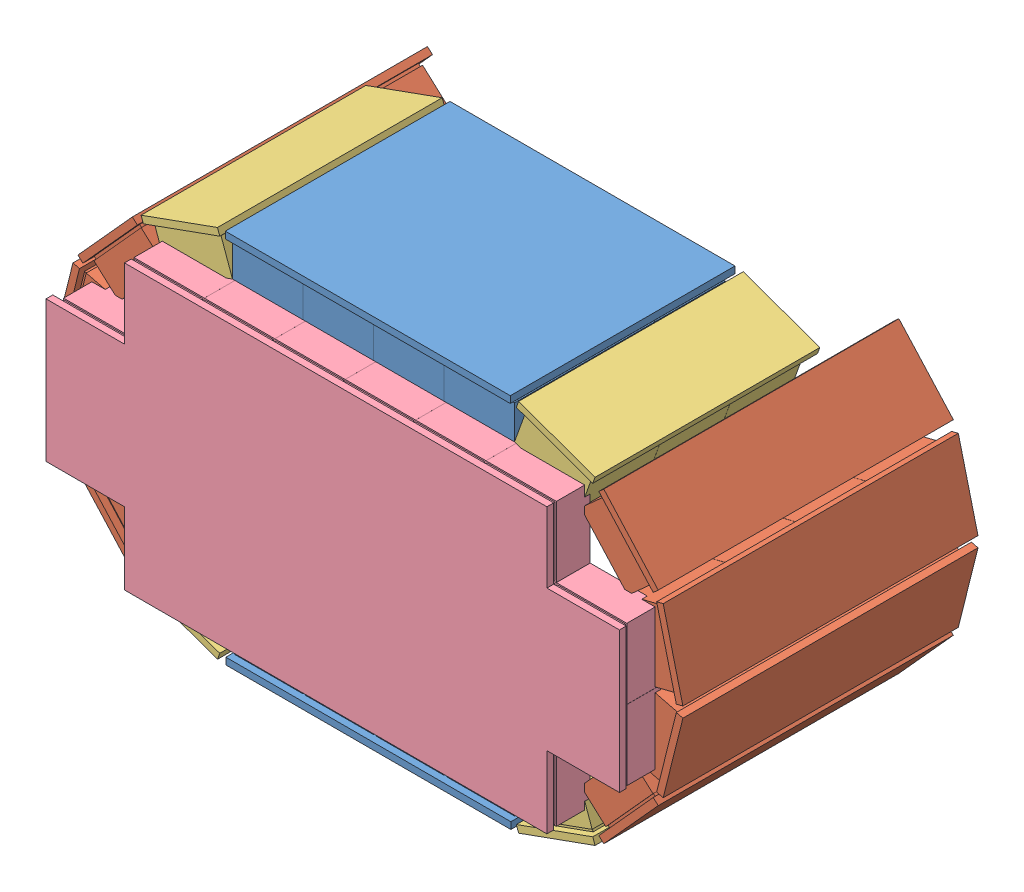
SolidWorks assembly detectorassem, configuration Default. Lengths in mm.
Overall size (517.67 317.54 241.94).
17 component instances, 4 part files, 12 mates.
Components (placement in the parent):
- 52mmTOPBOTTOM-1: 52mmTOPBOTTOM [Default] at (-69.8528 -35.4842 8.7442) size (210.55 32 166)
- SideDetector-1: SideDetector [Default] at (215.9367 233.9438 -54.2197) x (-0.242515 0.970148 0) z (0 0 1) size (268 155.36 218)
  - 52mmX4-1: 52mmX4 [Default] at (-99.1405 6.5957 36.9639) size (60 32 218)
  - 52mmX4-2: 52mmX4 [Default] at (-35.1412 22.594 36.9639) x (0.882373 0.47055 0) z (0 0 1) size (60 32 218)
  - 52mmX4-3: 52mmX4 [Default] at (-163.1399 22.594 36.9639) x (0.882373 -0.47055 0) z (0 0 1) size (60 32 218)
  - 52mmX4-4: 52mmX4 [Default] at (-212.0831 66.8254 36.9639) x (0.557166 -0.830401 0) z (0 0 1) size (60 32 218)
  - 52mmX3-1: 52mmX3 [Default] at (-234.4563 128.8843 62.9639) x (0.100883 -0.994898 0) z (0 0 1) size (60 32 166)
  - 52mmX3-2: 52mmX3 [Default] at (13.802 66.8254 62.9639) x (0.557166 0.830401 0) z (0 0 1) size (60 32 166)
- SideDetector-2: SideDetector [Default] at (-199.3424 -27.5859 -54.2197) x (0.242515 -0.970148 0) z (0 0 1) size (268 155.36 218)
  - 52mmX4-1: 52mmX4 [Default] at (-99.1405 6.5957 36.9639) size (60 32 218)
  - 52mmX4-2: 52mmX4 [Default] at (-35.1412 22.594 36.9639) x (0.882373 0.47055 0) z (0 0 1) size (60 32 218)
  - 52mmX4-3: 52mmX4 [Default] at (-163.1399 22.594 36.9639) x (0.882373 -0.47055 0) z (0 0 1) size (60 32 218)
  - 52mmX4-4: 52mmX4 [Default] at (-212.0831 66.8254 36.9639) x (0.557166 -0.830401 0) z (0 0 1) size (60 32 218)
  - 52mmX3-1: 52mmX3 [Default] at (-234.4563 128.8843 62.9639) x (0.100883 -0.994898 0) z (0 0 1) size (60 32 166)
  - 52mmX3-2: 52mmX3 [Default] at (13.802 66.8254 62.9639) x (0.557166 0.830401 0) z (0 0 1) size (60 32 166)
- 52mmTOPBOTTOM-2: 52mmTOPBOTTOM [Default] at (86.4472 241.8421 8.7442) x (-1 0 0) z (0 0 1) size (210.55 32 166)
- 52mmAnterior-2: 52mmAnterior [Default] at (34.3203 129.1897 115.6812) x (1 0 0) z (0 1 0) size (423.62 32 209.26)
Mates (geometry in assembly coordinates):
- Coincident1: coincident anti-aligned: line of 52mmTOPBOTTOM-1 through (112.4472 -3.4842 87.7442) axis (0 0 -1); line of SideDetector-1/52mmX3-1 through (112.4472 -3.4842 35.8442) axis (0 0 1)
- Coincident2: coincident: point of 52mmTOPBOTTOM-1; point of SideDetector-1/52mmX3-1
- Parallel1: parallel anti-aligned: line of 52mmTOPBOTTOM-1 through (-43.7528 -3.4842 87.7442) axis (1 0 0); line of 52mmTOPBOTTOM-2 through (8.2472 209.8421 87.7442) axis (-1 0 0)
- Parallel2: parallel anti-aligned: line of 52mmTOPBOTTOM-1 through (-95.8528 -3.4842 35.8442) axis (0 0 1); line of 52mmTOPBOTTOM-2 through (-95.8528 209.8421 87.7442) axis (0 0 -1)
- Coincident5: coincident anti-aligned: line of 52mmTOPBOTTOM-1 through (-95.8528 -3.4842 35.8442) axis (0 0 1); line of SideDetector-2/52mmX3-2 through (-95.8528 -3.4842 87.7442) axis (0 0 -1)
- Coincident6: coincident: point of 52mmTOPBOTTOM-1; point of SideDetector-2/52mmX3-2
- Coincident7: coincident anti-aligned: line of SideDetector-2/52mmX3-1 through (-95.8528 209.8421 35.8442) axis (0 0 1); line of 52mmTOPBOTTOM-2 through (-95.8528 209.8421 87.7442) axis (0 0 -1)
- Coincident8: coincident anti-aligned: line of SideDetector-1/52mmX3-2 through (112.4472 209.8421 87.7442) axis (0 0 -1); line of 52mmTOPBOTTOM-2 through (112.4472 209.8421 35.8442) axis (0 0 1)
- Coincident9: coincident: point of SideDetector-2/52mmX3-1; point of 52mmTOPBOTTOM-2
- Coincident11: coincident anti-aligned: line of 52mmTOPBOTTOM-1 through (-95.8528 -3.4842 87.7442) axis (0 -1 0); line of 52mmTOPBOTTOM-2 through (-95.8528 209.8421 87.7442) axis (0 1 0)
- Perpendicular3: perpendicular: plane of SideDetector-1/52mmX4-3 through (196.2308 52.7313 87.7442) normal (0 0 1); plane of 52mmAnterior-2 through (216.3503 52.2897 83.6812) normal (1 0 0)
- Lock1: lock: unknown of 52mmTOPBOTTOM-1; unknown of 52mmAnterior-2
